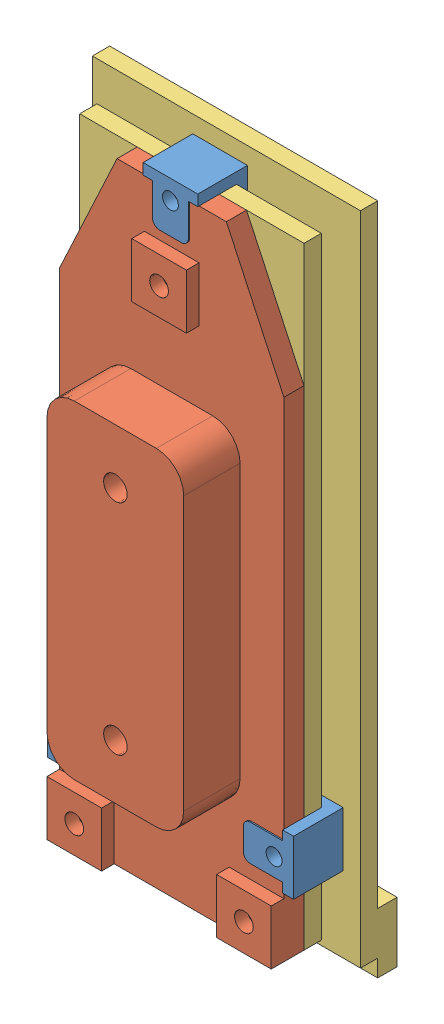
SolidWorks assembly CCID_20_assembly, configuration Default. Lengths in mm.
Overall size (31.14 78.2 17.16).
5 component instances, 3 part files, 12 mates.
Components (placement in the parent):
- clamp-1: clamp [Default] at (-8.0175 2.3048 0.8227) size (6.35 5.84 5.77)
- clamp-2: clamp [Default] at (-20.9325 -58.5352 0.8227) x (0 1 0) z (0 0 1) size (6.35 5.84 5.77)
- clamp-3: clamp [Default] at (4.8975 -58.5352 0.8227) x (0 -1 0) z (0 0 1) size (6.35 5.84 5.77)
- boat-1: boat [Default] at (-8.0175 -33.1402 6.4427) x (0 -1 0) z (0 0 -1) size (71.12 26.06 8.89)
- CCID20-1: CCID20 [Default] at (-8.0173 -33.1402 -1.9171) size (31.14 78.2 8.27)
Mates (geometry in assembly coordinates):
- Coincident1: coincident anti-aligned: plane of boat-1 through (31.4854 -68.7002 4.1027) normal (0 0 -1); plane of CCID20-1 through (-21.0475 -68.7002 4.1027) normal (0 0 1)
- Coincident3: coincident aligned: plane of boat-1 through (-21.0475 -11.9102 4.1027) normal (-1 0 0); plane of CCID20-1 through (-21.0475 2.4198 4.1027) normal (-1 0 0)
- Coincident4: coincident aligned: plane of boat-1 through (-21.0475 -68.7002 4.1027) normal (0 -1 0); plane of CCID20-1 through (-21.0475 -68.7002 4.1027) normal (0 -1 0)
- Distance1: distance = 0.2 mm anti-aligned: plane of ?; plane of ?
- Coincident9: coincident anti-aligned: plane of ?; plane of ?
- Coincident10: coincident anti-aligned: plane of ?; plane of ?
- Distance2: distance = 0.2 mm anti-aligned: plane of ?; plane of ?
- Coincident12: coincident anti-aligned: plane of ?; plane of ?
- Coincident13: coincident anti-aligned: plane of ?; plane of ?
- Distance3: distance = 0.2 mm anti-aligned: plane of ?; plane of ?
- Coincident15: coincident anti-aligned: plane of ?; plane of ?
- Coincident16: coincident anti-aligned: plane of ?; plane of ?
